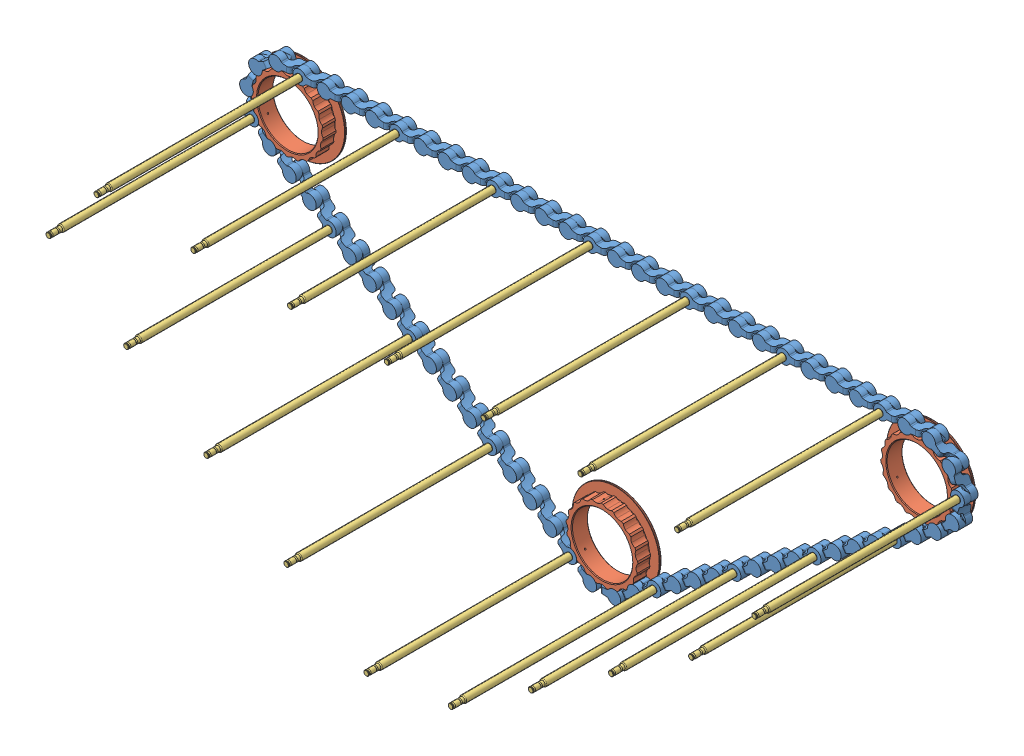
SolidWorks assembly 200-ChainLink, configuration Default. Lengths in mm.
Overall size (1353.31 582.01 407.99).
94 component instances, 5 part files, 45 mates.
Components (placement in the parent):
- 501-Link-1: 501-Link [Default] at origin size (70.32 25.4 25.4)
- 501-Link-74: 501-Link [with_dowell] at (41.0174 -12.6519 0) x (0.826245 -0.563311 0) z (0 0 1) (suppressed, hidden)
- 501-Link-75: 501-Link [with_dowell] at (-41.0174 -12.6519 0) x (0.826245 0.563311 0) z (0 0 1) (suppressed, hidden)
- 205-SprocketChainLink-1: 205-SprocketChainLink [Default] at origin size (162.8 162.8 30.16)
- 501-Link-2: 501-Link [Default] at (41.0225 -12.6555 0) x (0.826197 -0.563382 0) z (0 0 1) size (70.32 25.4 25.4)
- 501-Link-3: 501-Link [Default] at (67.7853 -46.2227 0) x (0.365202 -0.930928 0) z (0 0 1) size (70.32 25.4 25.4)
- 501-Link-4: 501-Link [Default] at (70.9855 -89.0335 0) x (-0.22274 -0.974878 0) z (0 0 1) size (70.32 25.4 25.4)
- 501-Link-6: 501-Link [Default] at (-44.92 0 0) size (70.32 25.4 25.4)
- 501-Link-7: 501-Link [Default] at (-89.84 0 0) size (70.32 25.4 25.4)
- 501-Link-8: 501-Link [Default] at (-134.76 0 0) size (70.32 25.4 25.4)
- 501-Link-9: 501-Link [Default] at (-179.68 0 0) size (70.32 25.4 25.4)
- 501-Link-10: 501-Link [Default] at (-224.6 0 0) size (70.32 25.4 25.4)
- 501-Link-11: 501-Link [Default] at (-269.52 0 0) size (70.32 25.4 25.4)
- 501-Link-12: 501-Link [Default] at (-314.44 0 0) size (70.32 25.4 25.4)
- 501-Link-13: 501-Link [Default] at (-359.36 0 0) size (70.32 25.4 25.4)
- 501-Link-14: 501-Link [Default] at (-404.28 0 0) size (70.32 25.4 25.4)
- 501-Link-15: 501-Link [Default] at (-449.2 0 0) size (70.32 25.4 25.4)
- 501-Link-16: 501-Link [Default] at (-494.12 0 0) size (70.32 25.4 25.4)
- 501-Link-17: 501-Link [Default] at (-539.04 0 0) size (70.32 25.4 25.4)
- 501-Link-5: 501-Link [Default] at (49.5106 -126.2066 0) x (-0.733255 -0.679953 0) z (0 0 1) size (70.32 25.4 25.4)
- 501-Link-31: 501-Link [Default] at (14.4475 -154.0761 0) x (-0.827884 -0.560899 0) z (0 0 1) size (70.32 25.4 25.4)
- 501-Link-32: 501-Link [Default] at (-22.741 -179.2717 0) x (-0.827884 -0.560899 0) z (0 0 1) size (70.32 25.4 25.4)
- 501-Link-33: 501-Link [Default] at (-59.9296 -204.4672 0) x (-0.827884 -0.560899 0) z (0 0 1) size (70.32 25.4 25.4)
- 501-Link-34: 501-Link [Default] at (-97.1181 -229.6628 0) x (-0.827884 -0.560899 0) z (0 0 1) size (70.32 25.4 25.4)
- 501-Link-35: 501-Link [Default] at (-134.3067 -254.8584 0) x (-0.827884 -0.560899 0) z (0 0 1) size (70.32 25.4 25.4)
- 501-Link-36: 501-Link [Default] at (-171.4953 -280.054 0) x (-0.827884 -0.560899 0) z (0 0 1) size (70.32 25.4 25.4)
- 501-Link-37: 501-Link [Default] at (-208.6838 -305.2496 0) x (-0.827884 -0.560899 0) z (0 0 1) size (70.32 25.4 25.4)
- 501-Link-38: 501-Link [Default] at (-245.8724 -330.4452 0) x (-0.827884 -0.560899 0) z (0 0 1) size (70.32 25.4 25.4)
- 501-Link-39: 501-Link [Default] at (-283.0609 -355.6408 0) x (-0.827884 -0.560899 0) z (0 0 1) size (70.32 25.4 25.4)
- 501-Link-40: 501-Link [Default] at (-320.2495 -380.8364 0) x (-0.827884 -0.560899 0) z (0 0 1) size (70.32 25.4 25.4)
- 501-Link-41: 501-Link [Default] at (-357.438 -406.032 0) x (-0.827884 -0.560899 0) z (0 0 1) size (70.32 25.4 25.4)
- 501-Link-42: 501-Link [Default] at (-394.6266 -431.2275 0) x (-0.827884 -0.560899 0) z (0 0 1) size (70.32 25.4 25.4)
- 501-Link-43: 501-Link [Default] at (-431.8151 -456.4231 0) x (-0.827884 -0.560899 0) z (0 0 1) size (70.32 25.4 25.4)
- 501-Link-18: 501-Link [Default] at (-583.96 0 0) size (70.32 25.4 25.4)
- 501-Link-44: 501-Link [Default] at (-469.0037 -481.6187 0) x (-0.827884 -0.560899 0) z (0 0 1) size (70.32 25.4 25.4)
- 501-Link-45: 501-Link [Default] at (-506.1923 -506.8143 0) x (-0.827884 -0.560899 0) z (0 0 1) size (70.32 25.4 25.4)
- 501-Link-19: 501-Link [Default] at (-628.88 0 0) size (70.32 25.4 25.4)
- 501-Link-20: 501-Link [Default] at (-673.8 0 0) size (70.32 25.4 25.4)
- 501-Link-21: 501-Link [Default] at (-718.72 0 0) size (70.32 25.4 25.4)
- 501-Link-22: 501-Link [Default] at (-763.64 0 0) size (70.32 25.4 25.4)
- 501-Link-23: 501-Link [Default] at (-808.56 0 0) size (70.32 25.4 25.4)
- 501-Link-24: 501-Link [Default] at (-853.48 0 0) size (70.32 25.4 25.4)
- 501-Link-25: 501-Link [Default] at (-898.4 0 0) size (70.32 25.4 25.4)
- 501-Link-26: 501-Link [Default] at (-943.32 0 0) size (70.32 25.4 25.4)
- 501-Link-27: 501-Link [Default] at (-988.24 0 0) size (70.32 25.4 25.4)
- 501-Link-28: 501-Link [Default] at (-1033.16 0 0) size (70.32 25.4 25.4)
- 501-Link-29: 501-Link [Default] at (-1078.08 0 0) size (70.32 25.4 25.4)
- 205-SprocketChainLink-2: 205-SprocketChainLink [Default] at (-1167.9198 0.1482 0) x (0.999978 -0.006595 0) z (0 0 1) size (162.8 162.8 30.16)
- 501-Link-69: 501-Link [Default] at (-1167.9202 0.1481 0) x (0.999978 -0.006595 0) z (0 0 1) size (70.32 25.4 25.4)
- 501-Link-70: 501-Link [Default] at (-1209.0252 -12.2367 0) x (0.829894 0.557921 0) z (0 0 1) size (70.32 25.4 25.4)
- 501-Link-71: 501-Link [Default] at (-1236.0085 -45.6268 0) x (0.371333 0.9285 0) z (0 0 1) size (70.32 25.4 25.4)
- 501-Link-72: 501-Link [Default] at (-1239.4907 -88.4156 0) x (-0.216306 0.976326 0) z (0 0 1) size (70.32 25.4 25.4)
- 501-Link-73: 501-Link [Default] at (-1218.2613 -125.7293 0) x (-0.728755 0.684774 0) z (0 0 1) size (70.32 25.4 25.4)
- 501-Link-54: 501-Link [Default] at (-1183.2993 -153.707 0) x (-0.827884 0.560899 0) z (0 0 1) size (70.32 25.4 25.4)
- 501-Link-55: 501-Link [Default] at (-1146.1107 -178.9026 0) x (-0.827884 0.560899 0) z (0 0 1) size (70.32 25.4 25.4)
- 501-Link-56: 501-Link [Default] at (-1108.9221 -204.0982 0) x (-0.827884 0.560899 0) z (0 0 1) size (70.32 25.4 25.4)
- 501-Link-57: 501-Link [Default] at (-1071.7336 -229.2938 0) x (-0.827884 0.560899 0) z (0 0 1) size (70.32 25.4 25.4)
- 501-Link-58: 501-Link [Default] at (-1034.545 -254.4894 0) x (-0.827884 0.560899 0) z (0 0 1) size (70.32 25.4 25.4)
- 501-Link-59: 501-Link [Default] at (-997.3565 -279.685 0) x (-0.827884 0.560899 0) z (0 0 1) size (70.32 25.4 25.4)
- 501-Link-60: 501-Link [Default] at (-960.1679 -304.8806 0) x (-0.827884 0.560899 0) z (0 0 1) size (70.32 25.4 25.4)
- 501-Link-61: 501-Link [Default] at (-922.9794 -330.0762 0) x (-0.827884 0.560899 0) z (0 0 1) size (70.32 25.4 25.4)
- 501-Link-62: 501-Link [Default] at (-885.7908 -355.2717 0) x (-0.827884 0.560899 0) z (0 0 1) size (70.32 25.4 25.4)
- 501-Link-63: 501-Link [Default] at (-848.6023 -380.4673 0) x (-0.827884 0.560899 0) z (0 0 1) size (70.32 25.4 25.4)
- 501-Link-64: 501-Link [Default] at (-811.4137 -405.6629 0) x (-0.827884 0.560899 0) z (0 0 1) size (70.32 25.4 25.4)
- 501-Link-65: 501-Link [Default] at (-774.2251 -430.8585 0) x (-0.827884 0.560899 0) z (0 0 1) size (70.32 25.4 25.4)
- 501-Link-66: 501-Link [Default] at (-737.0366 -456.0541 0) x (-0.827884 0.560899 0) z (0 0 1) size (70.32 25.4 25.4)
- 501-Link-67: 501-Link [Default] at (-699.848 -481.2497 0) x (-0.827884 0.560899 0) z (0 0 1) size (70.32 25.4 25.4)
- 501-Link-68: 501-Link [Default] at (-662.6595 -506.4453 0) x (-0.827884 0.560899 0) z (0 0 1) size (70.32 25.4 25.4)
- 205-SprocketChainLink-3: 205-SprocketChainLink [Default] at (-594.8073 -399.6616 0) x (0.989332 0.145676 0) z (0 0 1) size (162.8 162.8 30.16)
- 501-Link-53: 501-Link [Default] at (-543.3864 -532.0014 0) x (-0.828137 -0.560525 0) z (0 0 1) size (70.32 25.4 25.4)
- 501-Link-51: 501-Link [Default] at (-584.4462 -544.5156 0) x (-0.999994 0.003348 0) z (0 0 1) size (70.32 25.4 25.4)
- 501-Link-52: 501-Link [Default] at (-625.4188 -531.7233 0) x (-0.824259 0.566213 0) z (0 0 1) size (70.32 25.4 25.4)
- 203-RodPush-1: 203-RodPush [Default] at (0 0 190.5) size (12.7 12.7 400.05)
- 203-RodPush-2: 203-RodPush [Default] at (-143.4122 67.1768 190.5) x (1 -0.000513 0) z (0 0 1) size (12.7 12.7 400.05)
- 203-RodPush-3: 203-RodPush [Default] at (-323.0791 67.1768 190.5) x (1 -0.000513 0) z (0 0 1) size (12.7 12.7 400.05)
- 203-RodPush-4: 203-RodPush [Default] at (-502.746 67.1768 190.5) x (1 -0.000513 0) z (0 0 1) size (12.7 12.7 400.05)
- 203-RodPush-5: 203-RodPush [Default] at (-682.4129 67.1768 190.5) x (1 -0.000513 0) z (0 0 1) size (12.7 12.7 400.05)
- 203-RodPush-6: 203-RodPush [Default] at (-862.0798 67.1768 190.5) x (1 -0.000513 0) z (0 0 1) size (12.7 12.7 400.05)
- 203-RodPush-7: 203-RodPush [Default] at (-1041.7467 67.1768 190.5) x (1 -0.000513 0) z (0 0 1) size (12.7 12.7 400.05)
- 203-RodPush-8: 203-RodPush [Default] at (-1221.4136 67.1768 190.5) x (1 -0.000513 0) z (0 0 1) size (12.7 12.7 400.05)
- 203-RodPush-9: 203-RodPush [Default] at (-1310.6174 -43.2115 190.5) size (12.7 12.7 400.05)
- 203-RodPush-10: 203-RodPush [Default] at (-1166.3161 -149.5582 190.5) size (12.7 12.7 400.05)
- 203-RodPush-11: 203-RodPush [Default] at (-1017.5727 -250.3332 190.5) size (12.7 12.7 400.05)
- 203-RodPush-12: 203-RodPush [Default] at (-868.8293 -351.1082 190.5) size (12.7 12.7 400.05)
- 203-RodPush-13: 203-RodPush [Default] at (-720.0859 -451.8832 190.5) size (12.7 12.7 400.05)
- 203-RodPush-14: 203-RodPush [Default] at (-563.5863 -427.0787 190.5) size (12.7 12.7 400.05)
- 203-RodPush-15: 203-RodPush [Default] at (-414.8429 -326.3037 190.5) size (12.7 12.7 400.05)
- 203-RodPush-16: 203-RodPush [Default] at (-266.0995 -225.5287 190.5) size (12.7 12.7 400.05)
- 203-RodPush-17: 203-RodPush [Default] at (-117.3561 -124.7537 190.5) size (12.7 12.7 400.05)
- 800-LinkwithOpenHole-1: 800-LinkwithOpenHole [Default] at (-1122.9999 0 0) size (70.32 25.4 25.4)
  - 501-Link-1: 501-Link [Default] at origin size (70.32 25.4 25.4)
  - 507-SSBallNoseSpringPlunger_MC-3408A95-1: 507-SSBallNoseSpringPlunger_MC-3408A95 [Default] at (27.178 0 0) x (0 0 -1) z (1 0 0) (suppressed, hidden)
  - 504-Plug-1: 504-Plug [Default] at (34.925 0 0) x (0 0 -1) z (1 0 0) (suppressed, hidden)
  - 507-SSBallNoseSpringPlunger_MC-3408A95-3: 507-SSBallNoseSpringPlunger_MC-3408A95 [Default] at (-17.8444 2.4517 12.2076) x (0 -0.3861 -0.922457) z (1 0 0)
Mates (geometry in assembly coordinates):
- Coincident1: coincident anti-aligned: plane of 501-Link-1 through (28.81 -13.97 0) normal (0 0 1); plane of 501-Link-74 through (9.3438 -7.9656 0) normal (0 0 -1)
- Concentric1: concentric anti-aligned: circle of 501-Link-1; circle of 501-Link-74
- Coincident2: coincident aligned: unknown of ?
- Coincident3: coincident anti-aligned: plane of 501-Link-1 through (-28.81 -13.97 0) normal (0 0 -1); plane of 501-Link-75 through (-9.3438 -7.9656 0) normal (0 0 1)
- Concentric4: concentric anti-aligned: circle of 501-Link-1; circle of 501-Link-75
- Coincident4: coincident aligned: circle of 501-Link-74; circle of 501-Link-75
- InPlace1: in place: plane of assembly; plane of 205-SprocketChainLink-1; moOrthogonalPlaneRef_w of assembly; plane of 205-SprocketChainLink-1; moOrthogonalPlaneRef_w of assembly; plane of 205-SprocketChainLink-1
- Coincident5: coincident aligned: plane of 205-SprocketChainLink-1; plane of assembly
- Coincident6: coincident aligned: plane of 205-SprocketChainLink-1; moOrthogonalPlaneRef_w of assembly
- Coincident7: coincident anti-aligned: plane of 205-SprocketChainLink-1; moOrthogonalPlaneRef_w of assembly
- Coincident13: coincident anti-aligned: plane of 501-Link-5 through (18.8866 -135.5524 0) normal (0 0 1); plane of 501-Link-31 through (30.4631 -126.3511 0) normal (0 0 -1)
- Concentric7: concentric: cylinder of 501-Link-5 through (33.0418 -141.4783 -15.875) axis (0 0 -1) radius 4.7625; cylinder of 501-Link-31 through (33.0418 -141.4783 -12.7) axis (0 0 1) radius 4.8895
- Coincident14: coincident: plane of 501-Link-31; line of assembly
- Coincident19: coincident: axis of 205-SprocketChainLink-2 through (-1168.4 -72.6649 11.43) axis (0 0 -1); plane of assembly
- Coincident21: coincident aligned: plane of 205-SprocketChainLink-1 through (0 -72.8148 -17.4625) normal (0 0 -1); plane of 205-SprocketChainLink-2 through (-1168.4 -72.6649 -17.4625) normal (0 0 -1)
- Concentric11: concentric: cylinder of assembly through (-1190.3797 0.2962 -11.1125) axis (0 0 1) radius 12.7
- Coincident22: coincident anti-aligned: plane of 501-Link-73 through (-1187.6996 -135.2769 0) normal (0 0 -1); plane of 501-Link-54 through (-1199.3148 -125.982 0) normal (0 0 1)
- Concentric12: concentric: cylinder of 501-Link-73 through (-1201.8935 -141.1093 -12.7) axis (0 0 1) radius 4.8895; cylinder of 501-Link-54 through (-1201.8935 -141.1093 -15.875) axis (0 0 -1) radius 4.7625
- Parallel1: parallel: plane of 501-Link-54; line of assembly
- Coincident24: coincident aligned: plane of 205-SprocketChainLink-2 through (-1168.4 -72.6649 -17.4625) normal (0 0 -1); plane of 205-SprocketChainLink-3 through (-584.2 -471.6996 -17.4625) normal (0 0 -1)
- Coincident25: coincident: axis of 205-SprocketChainLink-3 through (-584.2 -471.6996 11.43) axis (0 0 -1); plane of assembly
- Concentric13: concentric anti-aligned: cylinder of 501-Link-45 through (-524.7865 -519.4121 12.7) axis (0 0 -1) radius 12.7; cylinder of 205-SprocketChainLink-3 through (-524.7865 -519.4121 -11.1125) axis (0 0 1) radius 12.7
- Coincident26: coincident anti-aligned: plane of 501-Link-45 through (-537.8793 -511.4082 0) normal (0 0 1); plane of 501-Link-53 through (-527.3584 -504.2837 0) normal (0 0 -1)
- Concentric14: concentric: cylinder of 501-Link-45 through (-524.7865 -519.4121 -15.875) axis (0 0 -1) radius 4.7625; cylinder of 501-Link-53 through (-524.7865 -519.4121 -12.7) axis (0 0 1) radius 4.8895
- Coincident27: coincident: line of 205-SprocketChainLink-3 through (-557.3957 -532.7495 -11.1125) axis (0 0 1); cylinder of 501-Link-53 through (-561.9863 -544.5908 12.7) axis (0 0 -1) radius 12.7
- Coincident28: coincident anti-aligned: plane of 501-Link-53 through (-575.0755 -536.5811 0) normal (0 0 1); plane of 501-Link-51 through (-555.5896 -530.6422 0) normal (0 0 -1)
- Concentric17: concentric: cylinder of 501-Link-53 through (-561.9863 -544.5908 -15.875) axis (0 0 -1) radius 4.7625; cylinder of 501-Link-51 through (-561.9863 -544.5908 -12.7) axis (0 0 1) radius 4.8895
- Coincident29: coincident: line of 205-SprocketChainLink-3 through (-596.4439 -537.2408 -11.1125) axis (0 0 1); cylinder of 501-Link-51 through (-606.906 -544.4404 12.7) axis (0 0 -1) radius 12.7
- Coincident30: coincident anti-aligned: plane of 501-Link-51 through (-613.2092 -530.4493 0) normal (0 0 1); plane of 501-Link-52 through (-593.7619 -536.521 0) normal (0 0 -1)
- Concentric19: concentric: cylinder of 501-Link-51 through (-606.906 -544.4404 -15.875) axis (0 0 -1) radius 4.7625; cylinder of 501-Link-52 through (-606.906 -544.4404 -12.7) axis (0 0 1) radius 4.8895
- InPlace2: in place: plane of assembly; plane of 203-RodPush-1; moOrthogonalPlaneRef_w of assembly; plane of 203-RodPush-1; moOrthogonalPlaneRef_w of assembly; plane of 203-RodPush-1
- Coincident31: coincident aligned: plane of 203-RodPush-1; plane of assembly
- Coincident32: coincident aligned: plane of 203-RodPush-1 through (0 0 190.5) normal (0 1 0); moOrthogonalPlaneRef_w of assembly
- Coincident33: coincident anti-aligned: plane of 203-RodPush-1 through (0 0 190.5) normal (1 0 0); moOrthogonalPlaneRef_w of assembly
- Concentric20: concentric: cylinder of 501-Link-6 through (-67.3799 0 -12.7) axis (0 0 1) radius 4.8895; cylinder of 203-RodPush-2 through (-67.3799 0 -15.875) axis (0 0 1) radius 4.8895
- Coincident34: coincident aligned: plane of 203-RodPush-1 through (75.9882 -67.1378 -9.525) normal (0 0 -1); plane of 203-RodPush-2 through (-67.4584 0 -9.525) normal (0 0 -1)
- Concentric21: concentric aligned: cylinder of 501-Link-73 through (-1234.6291 -110.3493 -11.43) axis (0 0 1) radius 4.7625; cylinder of 203-RodPush-9 through (-1234.6291 -110.3493 -9.525) axis (0 0 1) radius 4.7625
- Coincident35: coincident aligned: plane of 203-RodPush-8 through (-1145.4598 0 -9.525) normal (0 0 -1); plane of 203-RodPush-9 through (-1234.6291 -110.3493 -9.525) normal (0 0 -1)
- Concentric22: concentric aligned: cylinder of 501-Link-57 through (-1090.3278 -216.696 -11.43) axis (0 0 1) radius 4.7625; cylinder of 203-RodPush-10 through (-1090.3278 -216.696 -9.525) axis (0 0 1) radius 4.7625
- Coincident36: coincident aligned: plane of 203-RodPush-9 through (-1234.6291 -110.3493 -9.525) normal (0 0 -1); plane of 203-RodPush-10 through (-1090.3278 -216.696 -9.525) normal (0 0 -1)
- Concentric23: concentric: cylinder of 501-Link-45 through (-487.598 -494.2165 -12.7) axis (0 0 1) radius 4.8895; cylinder of 203-RodPush-14 through (-487.598 -494.2165 -9.525) axis (0 0 1) radius 4.7625
- Coincident37: coincident aligned: plane of 203-RodPush-13 through (-644.0977 -519.021 -9.525) normal (0 0 -1); plane of 203-RodPush-14 through (-487.598 -494.2165 -9.525) normal (0 0 -1)
- Coincident38: coincident anti-aligned: plane of 501-Link-69 through (-1139.203 -14.0116 0) normal (0 0 1); plane of 800-LinkwithOpenHole-1/501-Link-1 through (-1151.8099 -13.97 0) normal (0 0 -1)
- Concentric24: concentric anti-aligned: cylinder of 203-RodPush-8 through (-1145.4598 0 -9.525) axis (0 0 1) radius 4.7625; cylinder of 800-LinkwithOpenHole-1/501-Link-1 through (-1145.4598 0 11.43) axis (0 0 -1) radius 4.7625
- Concentric25: concentric aligned: cylinder of 501-Link-29 through (-1100.5399 0 12.7) axis (0 0 -1) radius 12.7; cylinder of 800-LinkwithOpenHole-1/501-Link-1 through (-1100.5399 0 12.7) axis (0 0 -1) radius 12.7
